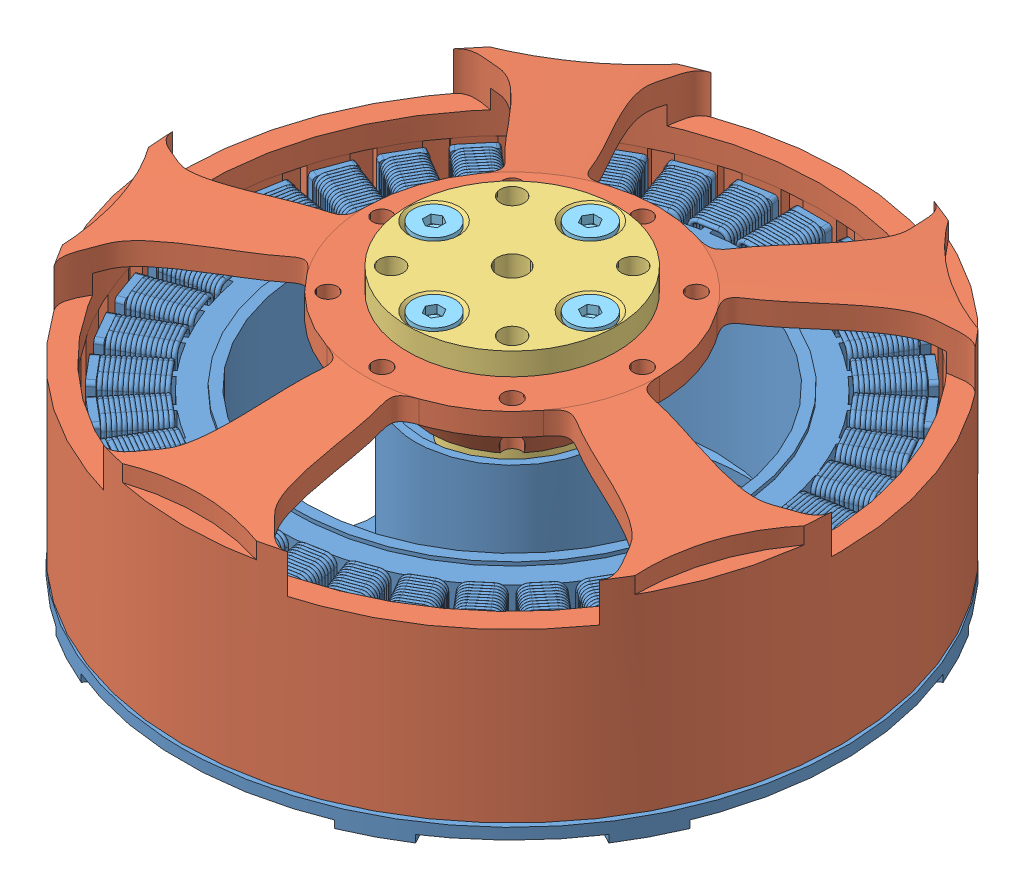
SolidWorks assembly TmotorU12plus, configuration Standard. Lengths in mm.
Overall size (92.58 43.52 89.93).
11 component instances, 5 part files, 12 mates.
Components (placement in the parent):
- 3501-Stator(Motor)-1: 3501-Stator(Motor) [Standard] at origin size (88.6 29.67 88.6)
- 3502-Rotor(Motor)-1: 3502-Rotor(Motor) [Standard] at (0 40 0) x (-1 0 0) z (0 0 -1) size (92.58 31.8 89.93)
- 3503-Verbindungsbolzen-1: 3503-Verbindungsbolzen [Standard] at (0 43 0) x (-1 0 0) z (0 0 -1) size (28 41 28)
- 3504-Halteplatte_für_Kugellager-1: 3504-Halteplatte_für_Kugellager [Standard] at (0 2 0) x (-1 0 0) z (0 0 1) size (23 2 23)
- socket csink head cap screw 10642_din-4: socket csink head cap screw 10642_din [ISO 10642 - M3 x 8 --- 8N] at (0 43 10.5) x (0 -1 0) z (0 0 1) size (8 5.54 5.54)
- socket csink head cap screw 10642_din-5: socket csink head cap screw 10642_din [ISO 10642 - M3 x 8 --- 8N] at (10.5 43 0) x (0 -1 0) z (1 0 0) size (8 5.54 5.54)
- socket csink head cap screw 10642_din-6: socket csink head cap screw 10642_din [ISO 10642 - M3 x 8 --- 8N] at (0 43 -10.5) x (0 -1 0) z (0 0 -1) size (8 5.54 5.54)
- socket csink head cap screw 10642_din-7: socket csink head cap screw 10642_din [ISO 10642 - M3 x 8 --- 8N] at (-10.5 43 0) x (0 -1 0) z (-1 0 0) size (8 5.54 5.54)
- socket csink head cap screw 10642_din-8: socket csink head cap screw 10642_din [ISO 10642 - M3 x 8 --- 8N] at (2.75 0 4.7631) x (0 1 0) z (0 0 1) size (8 5.54 5.54)
- socket csink head cap screw 10642_din-9: socket csink head cap screw 10642_din [ISO 10642 - M3 x 8 --- 8N] at (2.75 0 -4.7631) x (0 1 0) z (0.866025 0 -0.5) size (8 5.54 5.54)
- socket csink head cap screw 10642_din-10: socket csink head cap screw 10642_din [ISO 10642 - M3 x 8 --- 8N] at (-5.5 0 0) x (0 1 0) z (-0.866025 0 -0.5) size (8 5.54 5.54)
Mates (geometry in assembly coordinates):
- Abstand1: distance = 0.5 mm: plane of 3502-Rotor(Motor)-1 through (0 9.5 0) normal (0 -1 0); plane of 3501-Stator(Motor)-1 through (0 9 0) normal (0 1 0)
- Konzentrisch1: concentric: cylinder of 3501-Stator(Motor)-1 through (0 24 0) axis (0 1 0) radius 7.625; cylinder of 3502-Rotor(Motor)-1 through (0 42.7799 0) axis (0 1 0) radius 7.5
- Konzentrisch2: concentric: cylinder of 3502-Rotor(Motor)-1 through (0 42.7799 0) axis (0 1 0) radius 7.5; cylinder of 3503-Verbindungsbolzen-1 through (0 52.4149 0) axis (0 1 0) radius 7.5
- Konzentrisch3: concentric: cylinder of 3502-Rotor(Motor)-1 through (-8.1317 40 -8.1317) axis (0 1 0) radius 1.25; cylinder of 3503-Verbindungsbolzen-1 through (-8.1317 43 -8.1317) axis (0 1 0) radius 1.6
- Deckungsgleich1: coincident: plane of 3502-Rotor(Motor)-1 through (0 40 0) normal (0 1 0); plane of 3503-Verbindungsbolzen-1 through (-14 40 0) normal (0 -1 0)
- Konzentrisch4: concentric: cylinder of 3503-Verbindungsbolzen-1 through (0 43 0) axis (0 1 0) radius 2; cylinder of 3504-Halteplatte_für_Kugellager-1 through (0 0 0) axis (0 -1 0) radius 2
- Konzentrisch5: concentric: cylinder of 3503-Verbindungsbolzen-1 through (-5.5 2 0) axis (0 -1 0) radius 1.25; cylinder of 3504-Halteplatte_für_Kugellager-1 through (-5.5 0 0) axis (0 -1 0) radius 1.6
- Deckungsgleich2: coincident: plane of 3503-Verbindungsbolzen-1 through (-7.5 2 0) normal (0 -1 0); plane of 3504-Halteplatte_für_Kugellager-1 through (0 2 0) normal (0 1 0)
- Deckungsgleich5: coincident: cone of 3503-Verbindungsbolzen-1 through (0 43 10.5) axis (0 -1 0); cone of socket csink head cap screw 10642_din-4 through (0 42.41 10.5) axis (0 -1 0)
- Parallel2: parallel: plane of 3503-Verbindungsbolzen-1 through (0 43 0) normal (0 0 -1); plane of socket csink head cap screw 10642_din-4 through (0 43 10.5) normal (0 0 1)
- Deckungsgleich6: coincident: cone of 3504-Halteplatte_für_Kugellager-1 through (2.75 0 4.7631) axis (0 1 0); cone of socket csink head cap screw 10642_din-8 through (2.75 0.59 4.7631) axis (0 1 0)
- Parallel3: parallel: plane of socket csink head cap screw 10642_din-4 through (0 43 10.5) normal (0 0 1); plane of assembly through (0 0 0) normal (0 0 1)
